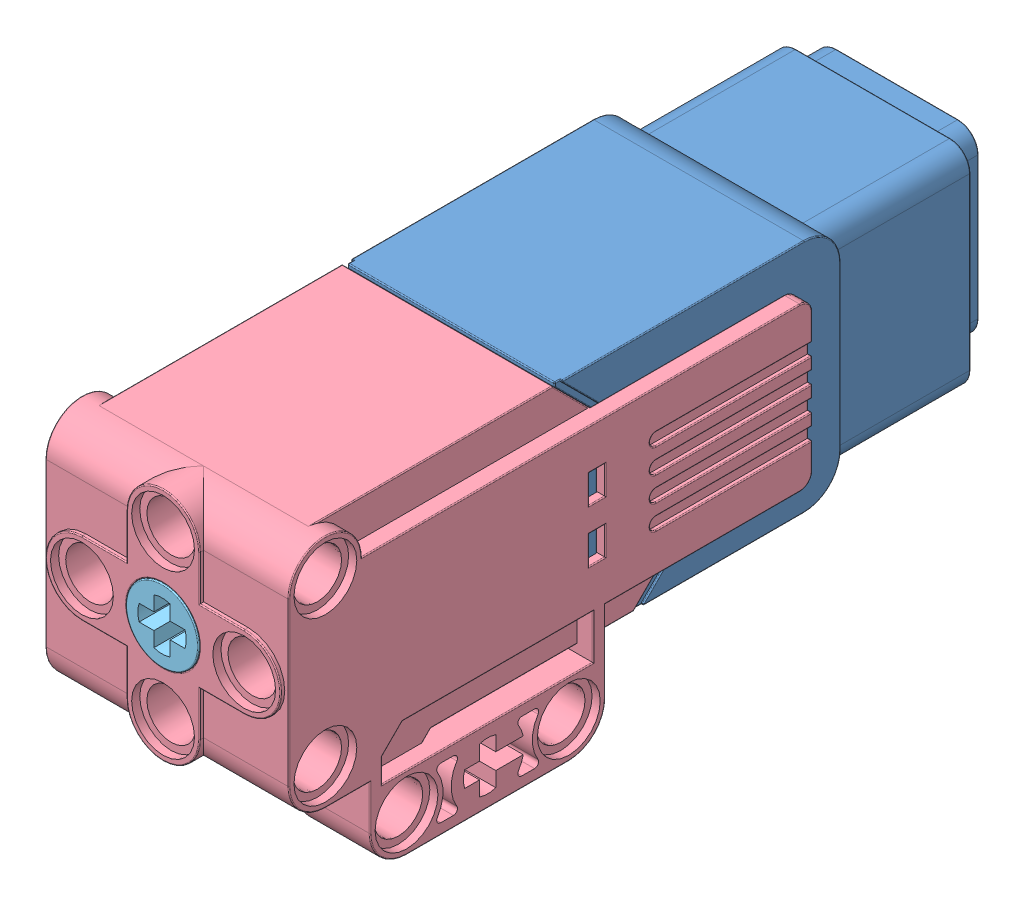
SolidWorks assembly LEGOEV3MEDIUMMOTOR, configuration Default. Lengths in mm.
Overall size (24 31.22 72.5).
7 component instances, 5 part files, 0 mates.
Components (placement in the parent):
- 99455.stp-1: 99455.stp [Default] at origin size (24 31.22 72.5)
  - 99535c01.stp-1: 99535c01.stp [Default] at origin size (24 31.22 72.4)
    - 99534-White.stp-1: 99534-White.stp [Default] at origin size (22.4 23.2 44.8)
    - 54732b-LtBluishGray.stp-1: 54732b-LtBluishGray.stp [Default] at (0 0.8 -16) x (-1 0 0) z (0 0 -1) size (12 14.56 14.4)
    - 99542-MilkyWhite.stp-1: 99542-MilkyWhite.stp [Default] at (0 0 48.4) x (1 0 0) z (0 0 -1) size (20.8 20.8 2.4)
    - 99535-LtBluishGray.stp-1: 99535-LtBluishGray.stp [Default] at (0 0 28.4) size (24 31.22 52)
  - 99543-Red.stp-1: 99543-Red.stp [Default] at (0 0 47.7) size (16 16 12.4)
